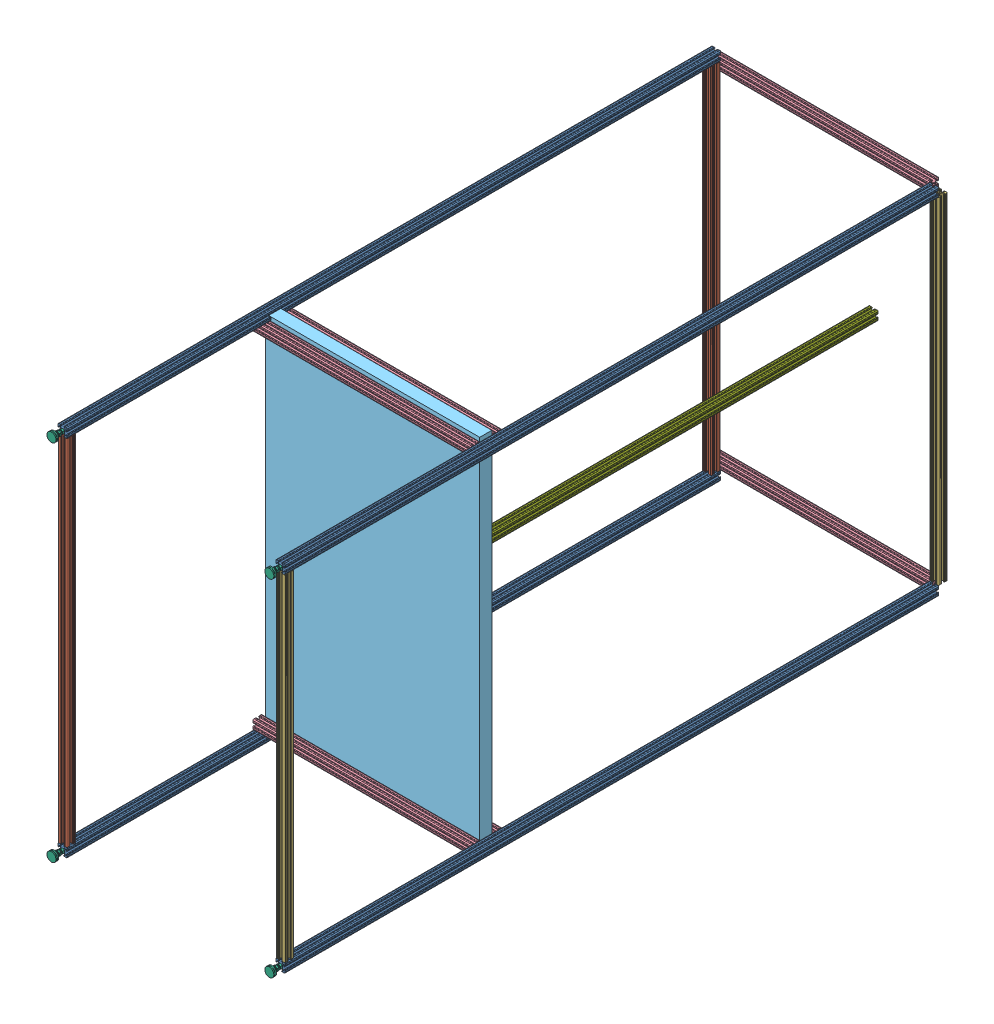
SolidWorks assembly sled, configuration Default. Lengths in mm.
Overall size (635.39 1042.02 2058.66).
20 component instances, 7 part files, 52 mates.
Components (placement in the parent):
- 6ft_t_slot-1: 6ft_t_slot [47065T209] at (493.282 1014.0758 1463.1185) size (25.4 25.4 1828.8)
- 6ft_t_slot-2: 6ft_t_slot [47065T209] at (1102.882 1039.4758 1463.1185) size (25.4 25.4 1828.8)
- 6ft_t_slot-3: 6ft_t_slot [47065T209] at (493.282 2030.6928 1463.1185) size (25.4 25.4 1828.8)
- 6ft_t_slot-4: 6ft_t_slot [47065T209] at (1102.882 2005.2928 1463.1185) size (25.4 25.4 1828.8)
- 3.3ft_t_slot-1: 3.3ft_t_slot [47065T209] at (493.282 1522.3843 2365.01) x (1 0 0) z (0 -1 0) size (25.48 25.48 990.6)
- 3.1ft_t_slot-2: 3.1ft_t_slot [47065T209] at (1102.882 1522.3843 2365.01) x (0 0 1) z (0 1 0) size (25.48 25.48 939.8)
- 2ft_t_slot-1: 2ft_t_slot [47065T209] at (785.0735 2005.2928 1758.2259) x (0 0 -1) z (1 0 0) size (25.48 25.48 609.6)
- 2ft_t_slot-4: 2ft_t_slot [47065T209] at (785.0735 2005.2928 1819.2429) x (0 0 -1) z (1 0 0) size (25.48 25.48 609.6)
- 2ft_t_slot-5: 2ft_t_slot [47065T209] at (785.0735 1039.4758 1819.2429) x (0 0 -1) z (1 0 0) size (25.48 25.48 609.6)
- 2ft_t_slot-7: 2ft_t_slot [47065T209] at (785.0735 1039.4758 1758.2259) x (0 0 1) z (-1 0 0) size (25.48 25.48 609.6)
- table_top-1: table_top [Default] at (789.3735 1527.5843 1772.4831) x (0 1 0) z (0 0 1) size (1000 600 34)
- 6111K820-1: 6111K820 [6111K82] at (493.282 1014.0758 2408.7394) x (1 0 0) z (0 1 0) size (25.4 52.91 25.4)
- 6111K820-2: 6111K820 [6111K82] at (1102.882 2005.2928 2408.7394) x (1 0 0) z (0 1 0) size (25.4 52.91 25.4)
- 6111K820-3: 6111K820 [6111K82] at (493.282 2030.6928 2408.7394) x (1 0 0) z (0 1 0) size (25.4 52.91 25.4)
- 6111K820-4: 6111K820 [6111K82] at (1102.882 1039.4758 2408.7394) x (1 0 0) z (0 1 0) size (25.4 52.91 25.4)
- 2ft_t_slot-8: 2ft_t_slot [47065T209] at (785.0735 1039.4758 536.227) x (0 0 1) z (-1 0 0) size (25.48 25.48 609.6)
- 2ft_t_slot-9: 2ft_t_slot [47065T209] at (785.0735 2005.2928 536.227) x (0 0 -1) z (1 0 0) size (25.48 25.48 609.6)
- 3.3ft_t_slot-3: 3.3ft_t_slot [47065T209] at (493.282 1522.3843 562.244) x (1 0 0) z (0 -1 0) size (25.48 25.48 990.6)
- 3.1ft_t_slot-3: 3.1ft_t_slot [47065T209] at (1102.882 1522.3843 536.227) x (1 0 0) z (0 -1 0) size (25.48 25.48 939.8)
- 5ft_t_slot-1: 5ft_t_slot [47065T209] at (734.865 1423.0758 1061.2831) size (25.48 25.48 1422.4)
Mates (geometry in assembly coordinates):
- Coincident1: coincident aligned: plane of 6ft_t_slot-1 through (488.7735 1012.9605 2377.5185) normal (-1 0 0); plane of 6ft_t_slot-3 through (488.7735 2029.5775 2377.5185) normal (-1 0 0)
- Coincident3: coincident aligned: plane of 6ft_t_slot-2 through (1107.3905 1038.3605 2377.5185) normal (1 0 0); plane of 6ft_t_slot-4 through (1107.3905 2004.1775 2377.5185) normal (1 0 0)
- Coincident5: coincident aligned: plane of 6ft_t_slot-1 through (482.7918 1024.566 548.7185) normal (0 0 -1); plane of 6ft_t_slot-2 through (1092.3918 1049.966 548.7185) normal (0 0 -1)
- Coincident6: coincident aligned: plane of 6ft_t_slot-1 through (482.7918 1024.566 548.7185) normal (0 0 -1); plane of 6ft_t_slot-3 through (482.7918 2041.183 548.7185) normal (0 0 -1)
- Coincident7: coincident aligned: plane of 6ft_t_slot-1 through (482.7918 1024.566 548.7185) normal (0 0 -1); plane of 6ft_t_slot-4 through (1092.3918 2015.783 548.7185) normal (0 0 -1)
- Distance1: distance = 25.4 mm aligned: plane of 6ft_t_slot-2 through (1101.7667 1034.9673 2377.5185) normal (0 -1 0); plane of 6ft_t_slot-1 through (492.1667 1009.5673 2377.5185) normal (0 -1 0)
- Distance2: distance = 25.4 mm aligned: plane of 6ft_t_slot-3 through (492.1667 2035.2013 2377.5185) normal (0 1 0); plane of 6ft_t_slot-4 through (1101.7667 2009.8013 2377.5185) normal (0 1 0)
- Distance3: distance = 8.5 mm anti-aligned: plane of 3.3ft_t_slot-1 through (482.7918 2017.6843 2375.5002) normal (0 1 0); plane of 6ft_t_slot-3 through (492.1667 2026.1843 2377.5185) normal (0 -1 0)
- Distance4: distance = 8.5 mm anti-aligned: plane of 3.3ft_t_slot-1 through (482.7918 1027.0843 2375.5002) normal (0 -1 0); plane of 6ft_t_slot-1 through (492.1667 1018.5843 2377.5185) normal (0 1 0)
- Coincident12: coincident aligned: plane of 6ft_t_slot-3 through (488.7735 2029.5775 2377.5185) normal (-1 0 0); plane of 3.3ft_t_slot-1 through (488.7735 1027.0843 2363.8948) normal (-1 0 0)
- Distance5: distance = 8 mm aligned: plane of 3.3ft_t_slot-1 through (492.1667 1027.0843 2369.5185) normal (0 0 1); plane of 6ft_t_slot-3 through (482.7918 2041.183 2377.5185) normal (0 0 1)
- Coincident21: coincident aligned: plane of 3.3ft_t_slot-1 through (492.1667 1027.0843 2360.5015) normal (0 0 -1); plane of 3.1ft_t_slot-2 through (1101.7667 1992.2843 2360.5015) normal (0 0 -1)
- Coincident22: coincident aligned: plane of 6ft_t_slot-4 through (1098.3735 2004.1775 2377.5185) normal (-1 0 0); plane of 3.1ft_t_slot-2 through (1098.3735 1992.2843 2363.8948) normal (-1 0 0)
- Distance8: distance = 8.5 mm anti-aligned: plane of 3.1ft_t_slot-2 through (1113.3722 1992.2843 2354.5198) normal (0 1 0); plane of 6ft_t_slot-4 through (1101.7667 2000.7843 2377.5185) normal (0 -1 0)
- Distance9: distance = 8.5 mm anti-aligned: plane of 2ft_t_slot-7 through (1089.8735 1049.966 1747.7357) normal (1 0 0); plane of 6ft_t_slot-2 through (1098.3735 1038.3605 2377.5185) normal (-1 0 0)
- Coincident25: coincident aligned: plane of 6ft_t_slot-2 through (1101.7667 1043.9843 2377.5185) normal (0 1 0); plane of 2ft_t_slot-7 through (480.2735 1043.9843 1757.1106) normal (0 1 0)
- Distance10: distance = 8.5 mm aligned: plane of 2ft_t_slot-7 through (480.2735 1049.966 1747.7357) normal (-1 0 0); plane of 6ft_t_slot-1 through (488.7735 1012.9605 2377.5185) normal (-1 0 0)
- Coincident27: coincident aligned: plane of 2ft_t_slot-5 through (480.2735 1049.966 1829.7331) normal (-1 0 0); plane of 2ft_t_slot-7 through (480.2735 1049.966 1747.7357) normal (-1 0 0)
- Coincident28: coincident aligned: plane of 2ft_t_slot-5 through (1089.8735 1043.9843 1820.3581) normal (0 1 0); plane of 2ft_t_slot-7 through (480.2735 1043.9843 1757.1106) normal (0 1 0)
- Distance11: distance = 52 mm anti-aligned: plane of 2ft_t_slot-5 through (1089.8735 1038.3605 1814.7344) normal (0 0 -1); plane of 2ft_t_slot-7 through (480.2735 1038.3605 1762.7344) normal (0 0 1)
- Coincident30: coincident aligned: plane of 2ft_t_slot-4 through (480.2735 2015.783 1829.7331) normal (-1 0 0); plane of 2ft_t_slot-5 through (480.2735 1049.966 1829.7331) normal (-1 0 0)
- Coincident32: coincident aligned: plane of 6ft_t_slot-4 through (1101.7667 2000.7843 2377.5185) normal (0 -1 0); plane of 2ft_t_slot-4 through (1089.8735 2000.7843 1820.3581) normal (0 -1 0)
- Coincident33: coincident aligned: plane of 2ft_t_slot-4 through (1089.8735 2004.1775 1823.7514) normal (0 0 1); plane of 2ft_t_slot-5 through (1089.8735 1038.3605 1823.7514) normal (0 0 1)
- Coincident34: coincident aligned: plane of 2ft_t_slot-1 through (480.2735 2015.783 1768.7161) normal (-1 0 0); plane of 2ft_t_slot-4 through (480.2735 2015.783 1829.7331) normal (-1 0 0)
- Coincident35: coincident aligned: plane of 2ft_t_slot-1 through (1089.8735 2000.7843 1759.3411) normal (0 -1 0); plane of 2ft_t_slot-4 through (1089.8735 2000.7843 1820.3581) normal (0 -1 0)
- Coincident37: coincident aligned: plane of 2ft_t_slot-1 through (1089.8735 2004.1775 1762.7344) normal (0 0 1); plane of 2ft_t_slot-7 through (480.2735 1038.3605 1762.7344) normal (0 0 1)
- Distance13: distance = 9 mm anti-aligned: plane of table_top-1 through (1089.3735 1027.5843 1806.4831) normal (0 -1 0); plane of 6ft_t_slot-1 through (492.1667 1018.5843 2377.5185) normal (0 1 0)
- Distance14: distance = 9 mm anti-aligned: plane of table_top-1 through (1089.3735 2027.5843 1806.4831) normal (1 0 0); plane of 6ft_t_slot-2 through (1098.3735 1038.3605 2377.5185) normal (-1 0 0)
- Distance15: distance = 8.2513 mm anti-aligned: plane of table_top-1 through (789.3735 1527.5843 1806.4831) normal (0 0 1); plane of 2ft_t_slot-5 through (1089.8735 1038.3605 1814.7344) normal (0 0 -1)
- Concentric1: concentric aligned: cylinder of 6ft_t_slot-2 through (1102.882 1039.4758 2377.5185) axis (0 0 -1) radius 2.6035; circle of 6111K820-4
- Coincident41: coincident anti-aligned: plane of 6ft_t_slot-1 through (482.7918 1024.566 2377.5185) normal (0 0 1); plane of 6111K820-4 through (1102.882 1045.8916 2377.5185) normal (0 0 -1)
- Concentric2: concentric aligned: cylinder of 6ft_t_slot-1 through (493.282 1014.0758 2377.5185) axis (0 0 -1) radius 2.6035; circle of 6111K820-1
- Coincident42: coincident anti-aligned: plane of 6ft_t_slot-1 through (482.7918 1024.566 2377.5185) normal (0 0 1); plane of 6111K820-1 through (493.282 1020.4916 2377.5185) normal (0 0 -1)
- Concentric3: concentric aligned: cylinder of 6ft_t_slot-3 through (493.282 2030.6928 2377.5185) axis (0 0 -1) radius 2.6035; circle of 6111K820-3
- Coincident43: coincident anti-aligned: plane of 6ft_t_slot-3 through (482.7918 2041.183 2377.5185) normal (0 0 1); plane of 6111K820-3 through (493.282 2037.1086 2377.5185) normal (0 0 -1)
- Concentric4: concentric aligned: cylinder of 6ft_t_slot-4 through (1102.882 2005.2928 2377.5185) axis (0 0 -1) radius 2.6035; circle of 6111K820-2
- Coincident44: coincident anti-aligned: plane of 6ft_t_slot-4 through (1092.3918 2015.783 2377.5185) normal (0 0 1); plane of 6111K820-2 through (1102.882 2011.7086 2377.5185) normal (0 0 -1)
- Distance16: distance = 8.5 mm anti-aligned: plane of 2ft_t_slot-8 through (1089.8735 1049.966 525.7368) normal (1 0 0); plane of 6ft_t_slot-2 through (1098.3735 1038.3605 2377.5185) normal (-1 0 0)
- Coincident46: coincident aligned: plane of 2ft_t_slot-7 through (480.2735 1043.9843 1757.1106) normal (0 1 0); plane of 2ft_t_slot-8 through (480.2735 1043.9843 535.1118) normal (0 1 0)
- Distance17: distance = 17 mm aligned: plane of 2ft_t_slot-8 through (480.2735 1038.3605 531.7185) normal (0 0 -1); plane of 6ft_t_slot-2 through (1092.3918 1049.966 548.7185) normal (0 0 -1)
- Coincident49: coincident aligned: plane of 6ft_t_slot-4 through (1101.7667 2009.8013 2377.5185) normal (0 1 0); plane of 2ft_t_slot-9 through (1089.8735 2009.8013 537.3423) normal (0 1 0)
- Coincident50: coincident aligned: plane of 2ft_t_slot-8 through (480.2735 1049.966 525.7368) normal (-1 0 0); plane of 2ft_t_slot-9 through (480.2735 2015.783 546.7172) normal (-1 0 0)
- Distance18: distance = 8.5 mm anti-aligned: plane of 3.3ft_t_slot-3 through (482.7918 2017.6843 572.7342) normal (0 1 0); plane of 6ft_t_slot-3 through (492.1667 2026.1843 2377.5185) normal (0 -1 0)
- Distance21: distance = 17 mm anti-aligned: plane of 2ft_t_slot-8 through (480.2735 1038.3605 540.7355) normal (0 0 1); plane of 3.3ft_t_slot-3 through (492.1667 1027.0843 557.7355) normal (0 0 -1)
- Distance22: distance = 8.5 mm aligned: plane of 3.3ft_t_slot-3 through (488.7735 1027.0843 561.1288) normal (-1 0 0); plane of 2ft_t_slot-8 through (480.2735 1049.966 525.7368) normal (-1 0 0)
- Coincident56: coincident aligned: plane of 2ft_t_slot-8 through (480.2735 1038.3605 531.7185) normal (0 0 -1); plane of 2ft_t_slot-9 through (1089.8735 2004.1775 531.7185) normal (0 0 -1)
- Distance23: distance = 8.5 mm anti-aligned: plane of 3.1ft_t_slot-3 through (1092.3918 1992.2843 546.7172) normal (0 1 0); plane of 6ft_t_slot-4 through (1101.7667 2000.7843 2377.5185) normal (0 -1 0)
- Coincident59: coincident aligned: plane of 6ft_t_slot-4 through (1107.3905 2004.1775 2377.5185) normal (1 0 0); plane of 3.1ft_t_slot-3 through (1107.3905 1052.4843 535.3574) normal (1 0 0)
- Coincident60: coincident aligned: plane of 2ft_t_slot-8 through (480.2735 1038.3605 531.7185) normal (0 0 -1); plane of 3.1ft_t_slot-3 through (1101.7667 1052.4843 531.7185) normal (0 0 -1)
- Coincident61: coincident: plane of table_top-1 through (789.3735 1527.5843 1772.4831) normal (0 0 -1); plane of 5ft_t_slot-1 through (724.3748 1433.566 1772.4831) normal (0 0 1)
- Distance24: distance = 350 mm: plane of 5ft_t_slot-1 through (739.3735 1421.9605 1772.4831) normal (1 0 0); plane of table_top-1 through (1089.3735 2027.5843 1806.4831) normal (1 0 0)
- Distance25: distance = 600 mm aligned: plane of 5ft_t_slot-1 through (733.7497 1427.5843 1772.4831) normal (0 1 0); plane of table_top-1 through (1089.3735 2027.5843 1806.4831) normal (0 1 0)
